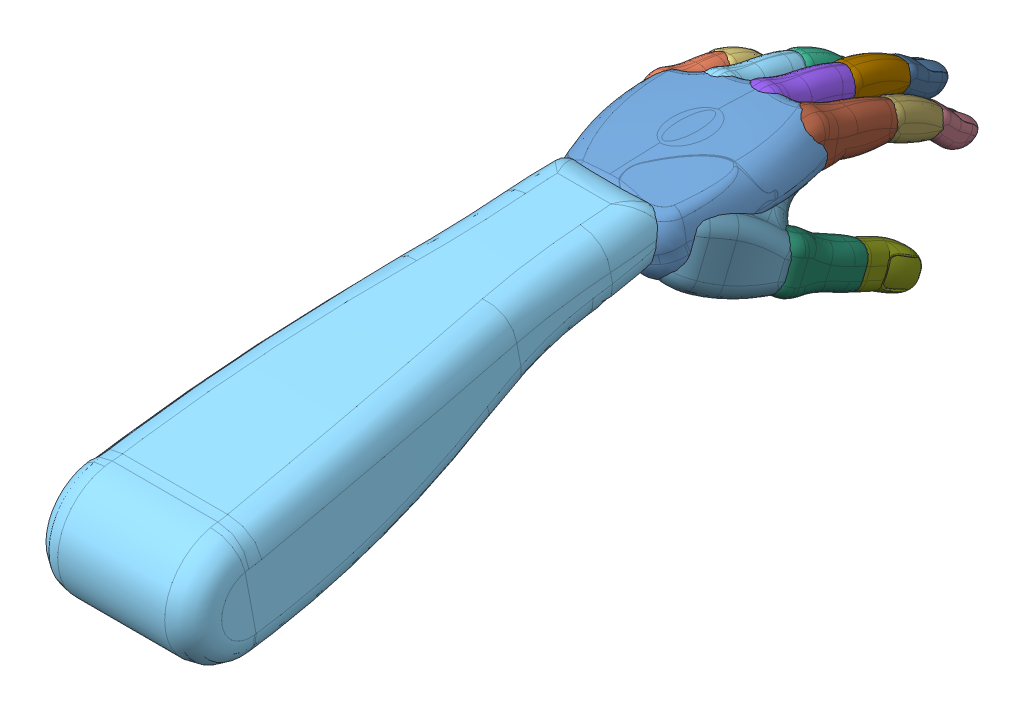
SolidWorks assembly Hand-mit-Arm-5d, configuration Standard. Lengths in mm.
Overall size (135.64 132.47 504.1).
23 component instances, 23 part files, 42 mates.
Components (placement in the parent):
- HF-5d-1: HF-5d [Standard] at origin size (96.85 52.09 117.71)
- K3-1: K3 [Standard] at (10.399 -18.6521 -83.3211) x (0.998483 0 -0.055052) z (0.054879 0.079164 0.99535) size (27.01 26.01 55)
- K2-1: K2 [Standard] at (8.4627 -21.5888 -118.4393) x (0.998483 0 -0.055052) z (0.049893 0.422663 0.904913) size (16.82 15.68 34)
- K1-1: K1 [Standard] at (7.3943 -30.9719 -137.8169) x (0.998483 0 -0.055052) z (0.037596 0.7305 0.681877) size (16 15.56 30)
- R3-1: R3 [Standard] at (30.0589 -15.4073 -95.0273) x (0.999729 0 0.023299) z (-0.023048 0.146547 0.988935) size (23.74 28.61 65)
- R2-1: R2 [Standard] at (31.1393 -23.3035 -141.3855) x (0.999729 0 0.023299) z (-0.020329 0.488596 0.872273) size (18 19.97 44)
- R1-1: R1 [Standard] at (31.7664 -38.7935 -168.2938) x (0.999729 0 0.023299) z (-0.017595 0.655499 0.754991) size (18 16.83 32)
- M3-1: M3 [Standard] at (50.4118 -15.343 -100.6074) x (0.998081 0 0.06192) z (-0.06146 0.121767 0.990654) size (25.17 30.31 68)
- M2-1: M2 [Standard] at (53.4131 -21.7947 -148.985) x (0.998081 0 0.06192) z (-0.059017 0.302646 0.951274) size (18.9 20.39 45)
- M1-1: M1 [Standard] at (55.2486 -31.761 -178.5717) x (0.998081 0 0.06192) z (-0.05013 0.587003 0.808031) size (18 17.57 33)
- Z3-1: Z3 [Standard] at (74.151 -17.2629 -102.6702) x (0.991781 0 0.127951) z (-0.125511 0.194338 0.972872) size (27.59 29 66)
- Z2-1: Z2 [Standard] at (79.9595 -26.7624 -147.6933) x (0.991781 0 0.127951) z (-0.116759 0.409011 0.905029) size (18.83 19.55 40)
- Z1-1: Z1 [Standard] at (82.899 -37.5357 -170.4784) x (0.991781 0 0.127951) z (-0.090622 0.705958 0.702432) size (18 17.52 32)
- D3d-1: D3d [Standard] at (103.0059 -42.4464 -55.2145) x (0 0.925587 -0.378534) z (0.642698 -0.290002 -0.709111) size (55.46 56.76 70)
- D2-1: D2 [Standard] at (106.4132 -44.0043 -59.024) x (0 -0.925587 0.378534) z (-0.232551 0.368156 0.900212) size (31.27 23.91 54)
- D1-1: D1 [Standard] at (114.8508 -58.1306 -93.5653) x (0 -0.925587 0.378534) z (-0.095032 0.376821 0.921398) size (24.93 23.5 40)
- Kugelgelenk-Z-1: Kugelgelenk-Z [Standard] at (74 -15.5 -101.5) x (0.991781 0 0.127951) z (-0.127951 0 0.991781) size (12 12 12)
- Kugelgelenk-K-1: Kugelgelenk-K [Standard] at (10.5 -16.5 -81.4884) x (0.998483 0 -0.055052) z (0.055052 0 0.998483) size (12 12 12)
- Kugelgelenk-M-1: Kugelgelenk-M [Standard] at (50.25 -12 -98) x (0.998081 0 0.06192) z (-0.06192 0 0.998081) size (12 12 12)
- Kugelgelenk-R-1: Kugelgelenk-R [Standard] at (30 -12 -92.5) x (0.999729 0 0.023299) z (-0.023299 0 0.999729) size (12 12 12)
- Kugelgelenk-D-1: Kugelgelenk-D [Standard] at (77 -26 -15) x (1 0 0) z (0 0.378534 0.925587) size (12 12 12)
- Kugelgelenk-H-1: Kugelgelenk-H [Standard] at (52.25 -13.5 -2.5) x (1 0 0) z (0 -0.95434 0.298721) size (12 12 12)
- Unterarm-V2-1: Unterarm-V2 [Standard] at (52.25 -65.6813 257.6284) x (1 0 0) z (0 -0.183099 0.983094) size (110.54 75.93 315.79)
Mates (geometry in assembly coordinates):
- Deckungsgleich1: coincident aligned: circle of K3-1; circle of K2-1
- Deckungsgleich2: coincident aligned: circle of K2-1; circle of K1-1
- Deckungsgleich3: coincident aligned: circle of R2-1; circle of R1-1
- Deckungsgleich4: coincident aligned: circle of R3-1; circle of R2-1
- Deckungsgleich5: coincident aligned: circle of M2-1; circle of M1-1
- Deckungsgleich6: coincident aligned: circle of M3-1; circle of M2-1
- Deckungsgleich7: coincident aligned: circle of Z2-1; circle of Z1-1
- Deckungsgleich8: coincident aligned: circle of Z3-1; circle of Z2-1
- Deckungsgleich9: coincident aligned: circle of D2-1; circle of D1-1
- Deckungsgleich10: coincident aligned: circle of Z3-1; circle of Kugelgelenk-Z-1
- Deckungsgleich11: coincident aligned: circle of HF-5d-1; circle of Kugelgelenk-Z-1
- Deckungsgleich12: coincident aligned: circle of HF-5d-1; circle of Kugelgelenk-K-1
- Deckungsgleich13: coincident aligned: circle of K3-1; circle of Kugelgelenk-K-1
- Deckungsgleich14: coincident aligned: circle of HF-5d-1; circle of Kugelgelenk-M-1
- Deckungsgleich15: coincident aligned: circle of M3-1; circle of Kugelgelenk-M-1
- Deckungsgleich16: coincident aligned: circle of HF-5d-1; circle of Kugelgelenk-R-1
- Deckungsgleich17: coincident aligned: circle of R3-1; circle of Kugelgelenk-R-1
- Deckungsgleich18: coincident anti-aligned: circle of HF-5d-1; circle of Kugelgelenk-D-1
- Deckungsgleich19: coincident anti-aligned: circle of D2-1; circle of D3d-1
- Deckungsgleich20: coincident aligned: circle of Kugelgelenk-D-1; circle of D3d-1
- KurvengetriebeTangential1: cam tangent: cylinder of K2-1 through (3.8249 -41.7282 -111.7312) axis (0.998483 0 -0.055052) radius 0.5; cylinder of K1-1 through (3.9273 -38.2245 -109.8742) axis (0.998483 0 -0.055052) radius 0.5; cylinder of K1-1 through (3.8249 -41.7282 -111.7312) axis (0.998483 0 -0.055052) radius 0.5; cylinder of K1-1 through (3.9501 -40.6899 -109.4605) axis (0.998483 0 -0.055052) radius 3; cylinder of K1-1 through (3.9501 -40.6899 -109.4605) axis (0.998483 0 -0.055052) radius 2
- KurvengetriebeTangential3: cam tangent: cylinder of R2-1 through (26.7916 -33.7908 -169.4321) axis (0.999729 0 0.023299) radius 0.5; cylinder of R1-1 through (26.7631 -35.9721 -168.211) axis (0.999729 0 0.023299) radius 2; cylinder of R1-1 through (26.7631 -35.9721 -168.211) axis (0.999729 0 0.023299) radius 3; cylinder of R1-1 through (26.7191 -34.3334 -166.3235) axis (0.999729 0 0.023299) radius 0.5; cylinder of R1-1 through (26.8114 -34.5726 -170.2819) axis (0.999729 0 0.023299) radius 0.5
- KurvengetriebeTangential4: cam tangent: cylinder of M2-1 through (50.2775 -26.5851 -179.1921) axis (0.998081 0 0.06192) radius 0.5; cylinder of M1-1 through (50.2307 -28.9679 -178.437) axis (0.998081 0 0.06192) radius 2; cylinder of M1-1 through (50.2307 -28.9679 -178.437) axis (0.998081 0 0.06192) radius 3; cylinder of M1-1 through (50.1053 -27.5004 -176.4169) axis (0.998081 0 0.06192) radius 0.5; cylinder of M1-1 through (50.3509 -27.3927 -180.3746) axis (0.998081 0 0.06192) radius 0.5
- KurvengetriebeTangential6: cam tangent: cylinder of Z2-1 through (78.0705 -33.1331 -172.1289) axis (0.991781 0 0.127951) radius 0.5; cylinder of Z1-1 through (78.2164 -34.1609 -173.26) axis (0.991781 0 0.127951) radius 0.5; cylinder of Z1-1 through (77.9396 -35.4144 -171.1147) axis (0.991781 0 0.127951) radius 2; cylinder of Z1-1 through (77.9396 -35.4144 -171.1147) axis (0.991781 0 0.127951) radius 3; cylinder of Z1-1 through (77.7131 -33.6495 -169.3587) axis (0.991781 0 0.127951) radius 0.5
- KurvengetriebeTangential7: cam tangent: cylinder of D2-1 through (118.4429 -51.9097 -91.563) axis (0 -0.925587 0.378534) radius 0.5; cylinder of D1-1 through (116.0114 -52.1298 -92.1012) axis (0 -0.925587 0.378534) radius 2; cylinder of D1-1 through (116.0114 -52.1298 -92.1012) axis (0 -0.925587 0.378534) radius 3; cylinder of D1-1 through (118.5001 -52.0399 -91.8813) axis (0 -0.925587 0.378534) radius 0.5; cylinder of D1-1 through (115.7738 -51.1877 -89.7977) axis (0 -0.925587 0.378534) radius 0.5
- KurvengetriebeTangential8: cam tangent: cylinder of K3-1 through (3.4727 -18.4322 -118.1202) axis (0.998483 0 -0.055052) radius 0.5; cylinder of K2-1 through (3.4254 -18.6586 -118.9776) axis (0.998483 0 -0.055052) radius 0.5; cylinder of K2-1 through (3.4836 -20.9244 -117.9226) axis (0.998483 0 -0.055052) radius 2; cylinder of K2-1 through (3.4836 -20.9244 -117.9226) axis (0.998483 0 -0.055052) radius 3; cylinder of K2-1 through (3.6207 -20.7063 -115.4359) axis (0.998483 0 -0.055052) radius 0.5
- KurvengetriebeTangential9: cam tangent: cylinder of R3-1 through (26.1179 -16.0667 -140.5249) axis (0.999729 0 0.023299) radius 0.5; cylinder of R2-1 through (26.1378 -16.3584 -141.3798) axis (0.999729 0 0.023299) radius 0.5; cylinder of R2-1 through (26.1094 -18.5397 -140.1586) axis (0.999729 0 0.023299) radius 2; cylinder of R2-1 through (26.1094 -18.5397 -140.1586) axis (0.999729 0 0.023299) radius 3; cylinder of R2-1 through (26.0519 -18.1379 -137.6918) axis (0.999729 0 0.023299) radius 0.5
- KurvengetriebeTangential10: cam tangent: cylinder of M3-1 through (48.3207 -15.5461 -147.6508) axis (0.998081 0 0.06192) radius 0.5; cylinder of M2-1 through (48.3487 -15.6447 -148.1021) axis (0.998081 0 0.06192) radius 0.5; cylinder of M2-1 through (48.3018 -18.0275 -147.347) axis (0.998081 0 0.06192) radius 2; cylinder of M2-1 through (48.3018 -18.0275 -147.347) axis (0.998081 0 0.06192) radius 3; cylinder of M2-1 through (48.1472 -18.1314 -144.8539) axis (0.998081 0 0.06192) radius 0.5
- KurvengetriebeTangential11: cam tangent: cylinder of Z3-1 through (74.9017 -21.0063 -147.5665) axis (0.991781 0 0.127951) radius 0.5; cylinder of Z2-1 through (74.9703 -21.1773 -148.0987) axis (0.991781 0 0.127951) radius 0.5; cylinder of Z2-1 through (74.8395 -23.4586 -147.0846) axis (0.991781 0 0.127951) radius 2; cylinder of Z2-1 through (74.8395 -23.4586 -147.0846) axis (0.991781 0 0.127951) radius 3; cylinder of Z2-1 through (74.5204 -23.278 -144.6116) axis (0.991781 0 0.127951) radius 0.5
- KurvengetriebeTangential12: cam tangent: cylinder of D2-1 through (108.6333 -38.0078 -57.5702) axis (0 -0.925587 0.378534) radius 3; cylinder of D2-1 through (108.6333 -38.0078 -57.5702) axis (0 -0.925587 0.378534) radius 2; cylinder of D2-1 through (111.0648 -37.7877 -57.0321) axis (0 -0.925587 0.378534) radius 0.5; cylinder of D2-1 through (108.052 -37.0874 -55.3197) axis (0 -0.925587 0.378534) radius 0.5; cylinder of D3d-1 through (110.5486 -46.6555 -52.2977) axis (0 0.925587 -0.378534) radius 0.5
- KurvengetriebeTangential13: cam tangent: cylinder of K3-1 through (5.4504 -14.2258 -82.2499) axis (0.998483 0 -0.055052) radius 0.5; cylinder of K3-1 through (5.5076 -16.5 -81.2132) axis (0.998483 0 -0.055052) radius 2; cylinder of K3-1 through (5.5076 -16.5 -81.2132) axis (0.998483 0 -0.055052) radius 3; cylinder of K3-1 through (5.6402 -17.1664 -78.8073) axis (0.998483 0 -0.055052) radius 0.5; cylinder of Kugelgelenk-K-1 through (5.5076 -14 -81.2132) axis (0.998483 0 -0.055052) radius 0.5
- KurvengetriebeTangential14: cam tangent: cylinder of HF-5d-1 through (10.7179 -21.5 -83.9789) axis (0 1 0) radius 0.5; cylinder of HF-5d-1 through (10.5 -21.5 -81.4884) axis (0 1 0) radius 2; cylinder of HF-5d-1 through (10.5 -21.5 -81.4884) axis (0 1 0) radius 3; cylinder of HF-5d-1 through (8.5849 -21.5 -83.0954) axis (0 1 0) radius 0.5; cylinder of Kugelgelenk-K-1 through (10.5 -21.5 -83.9884) axis (0 1 0) radius 0.5
- KurvengetriebeTangential15: cam tangent: cylinder of HF-5d-1 through (30.2179 -17 -94.9905) axis (0 1 0) radius 0.5; cylinder of HF-5d-1 through (30 -17 -92.5) axis (0 1 0) radius 3; cylinder of HF-5d-1 through (30 -17 -92.5) axis (0 1 0) radius 2; cylinder of HF-5d-1 through (28.0849 -17 -94.107) axis (0 1 0) radius 0.5; cylinder of Kugelgelenk-R-1 through (30 -17 -95) axis (0 1 0) radius 0.5
- KurvengetriebeTangential16: cam tangent: cylinder of HF-5d-1 through (50.25 -7 -98) axis (0 -1 0) radius 3; cylinder of HF-5d-1 through (49 -7 -100.1651) axis (0 -1 0) radius 0.5; cylinder of HF-5d-1 through (50.25 -7 -98) axis (0 -1 0) radius 2; cylinder of HF-5d-1 through (50.897 -7 -100.4148) axis (0 -1 0) radius 0.5; cylinder of Kugelgelenk-M-1 through (50.25 -17 -100.5) axis (0 1 0) radius 0.5
- KurvengetriebeTangential18: cam tangent: cylinder of R3-1 through (25 -12 -92.5) axis (1 0 0) radius 3; cylinder of R3-1 through (25 -9.6508 -93.3551) axis (1 0 0) radius 0.5; cylinder of R3-1 through (25 -12 -92.5) axis (1 0 0) radius 2; cylinder of R3-1 through (25 -12.8551 -90.1508) axis (1 0 0) radius 0.5; cylinder of Kugelgelenk-R-1 through (25 -9.5 -92.5) axis (1 0 0) radius 0.5
- KurvengetriebeTangential19: cam tangent: cylinder of M3-1 through (45.25 -12 -98) axis (1 0 0) radius 3; cylinder of M3-1 through (45.25 -9.6508 -98.8551) axis (1 0 0) radius 0.5; cylinder of M3-1 through (45.25 -12 -98) axis (1 0 0) radius 2; cylinder of M3-1 through (45.25 -12.8551 -95.6508) axis (1 0 0) radius 0.5; cylinder of Kugelgelenk-M-1 through (45.25 -9.5 -98) axis (1 0 0) radius 0.5
- KurvengetriebeTangential21: cam tangent: cylinder of Z3-1 through (69.049 -13.1344 -102.5686) axis (0.998637 0 0.052184) radius 0.5; cylinder of Z3-1 through (69.0068 -15.5 -101.7609) axis (0.998637 0 0.052184) radius 2; cylinder of Z3-1 through (69.0068 -15.5 -101.7609) axis (0.998637 0 0.052184) radius 3; cylinder of Z3-1 through (68.8851 -16.401 -99.4321) axis (0.998637 0 0.052184) radius 0.5; cylinder of Kugelgelenk-Z-1 through (69.0068 -13 -101.7609) axis (0.998637 0 0.052184) radius 0.5
- KurvengetriebeTangential22: cam tangent: cylinder of HF-5d-1 through (75.25 -10.5 -103.6651) axis (0 -1 0) radius 0.5; cylinder of HF-5d-1 through (74 -10.5 -101.5) axis (0 -1 0) radius 3; cylinder of HF-5d-1 through (72.75 -10.5 -103.6651) axis (0 -1 0) radius 0.5; cylinder of HF-5d-1 through (74 -10.5 -101.5) axis (0 -1 0) radius 2; cylinder of Kugelgelenk-Z-1 through (74 -20.5 -104) axis (0 1 0) radius 0.5
- KurvengetriebeTangential23: cam tangent: cylinder of HF-5d-1 through (73 -23.5095 -14.7821) axis (1 0 0) radius 0.5; cylinder of HF-5d-1 through (73 -26 -15) axis (1 0 0) radius 3; cylinder of HF-5d-1 through (73 -26 -15) axis (1 0 0) radius 2; cylinder of HF-5d-1 through (73 -24.2322 -16.7678) axis (1 0 0) radius 0.5; cylinder of Kugelgelenk-D-1 through (73 -23.5007 -15.0608) axis (1 0 0) radius 0.5
- KurvengetriebeTangential24: cam tangent: cylinder of D3d-1 through (77 -30.6279 -13.1073) axis (0 0.925587 -0.378534) radius 3; cylinder of D3d-1 through (77 -30.6279 -13.1073) axis (0 0.925587 -0.378534) radius 2; cylinder of D3d-1 through (75.7497 -31.4474 -15.1112) axis (0 0.925587 -0.378534) radius 0.5; cylinder of D3d-1 through (77.4338 -31.5599 -15.3862) axis (0 0.925587 -0.378534) radius 0.5; cylinder of Kugelgelenk-D-1 through (77 -31.5743 -15.4213) axis (0 0.925587 -0.378534) radius 0.5
- Deckungsgleich21: coincident aligned: circle of HF-5d-1; circle of Kugelgelenk-H-1
- Deckungsgleich22: coincident aligned: circle of Kugelgelenk-H-1; circle of Unterarm-V2-1
